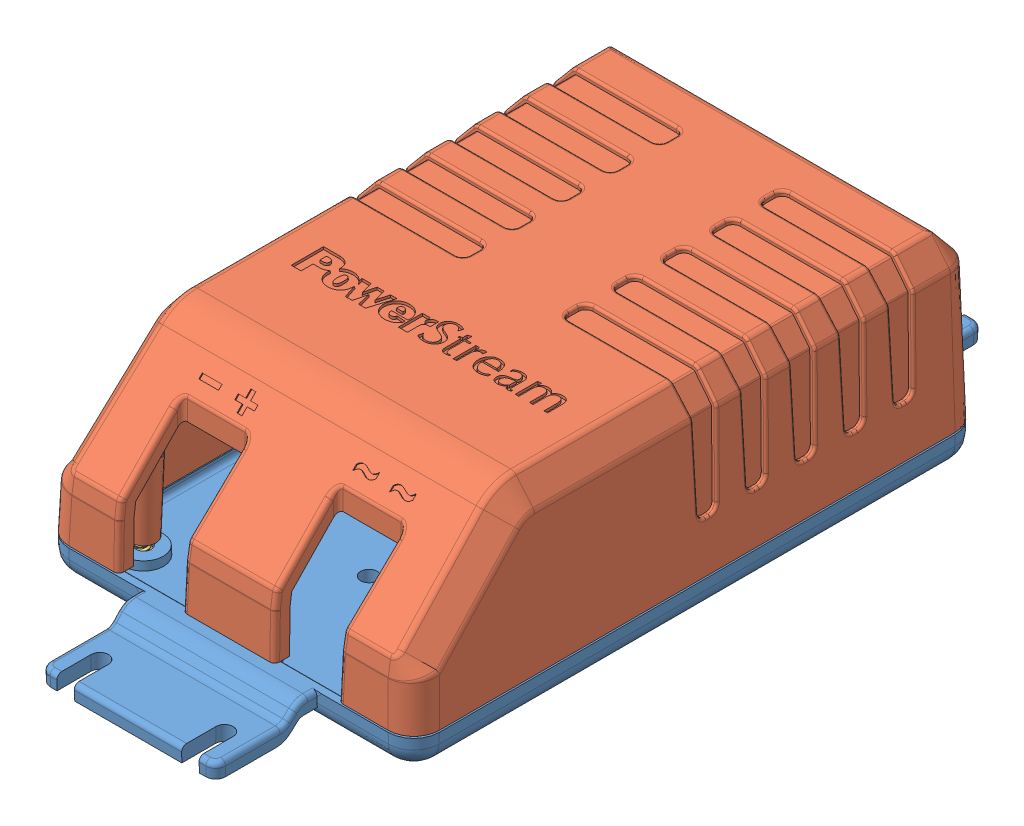
SolidWorks assembly Cases assembly, configuration Default. Lengths in mm.
Overall size (75.42 39.36 156.35).
3 component instances, 3 part files, 4 mates.
Components (placement in the parent):
- PST-INV2424_base-1: PST-INV2424_base [Default] at origin size (75.42 6 156.35)
- PST-INV2424_Top-1: PST-INV2424_Top [Default] at (0 6.3528 0) size (75.42 34.76 115.42)
- 90385A110-1: 90385A110 [90385A110] at (-26.67 2.3622 48.3235) x (1 0 0) z (0 -1 0) size (4.9 4.9 14.83)
Mates (geometry in assembly coordinates):
- Concentric1: concentric anti-aligned: cylinder of PST-INV2424_base-1 through (26.67 0 48.3235) axis (0 1 0) radius 1.5557; cylinder of PST-INV2424_Top-1 through (26.67 28.1985 48.3235) axis (0 -1 0) radius 1.5
- Concentric2: concentric anti-aligned: cylinder of PST-INV2424_base-1 through (-26.67 0 48.3235) axis (0 1 0) radius 1.5557; cylinder of PST-INV2424_Top-1 through (-26.67 28.1985 48.3235) axis (0 -1 0) radius 1.5
- Concentric3: concentric anti-aligned: cylinder of PST-INV2424_Top-1 through (-26.67 28.1985 48.3235) axis (0 -1 0) radius 1.5; cylinder of 90385A110-1 through (-26.67 2.3622 48.3235) axis (0 1 0) radius 0.8495
- Coincident1: coincident anti-aligned: plane of PST-INV2424_base-1 through (-26.67 2.3622 48.3235) normal (0 -1 0); plane of 90385A110-1 through (-26.67 2.3622 48.3235) normal (0 1 0)
